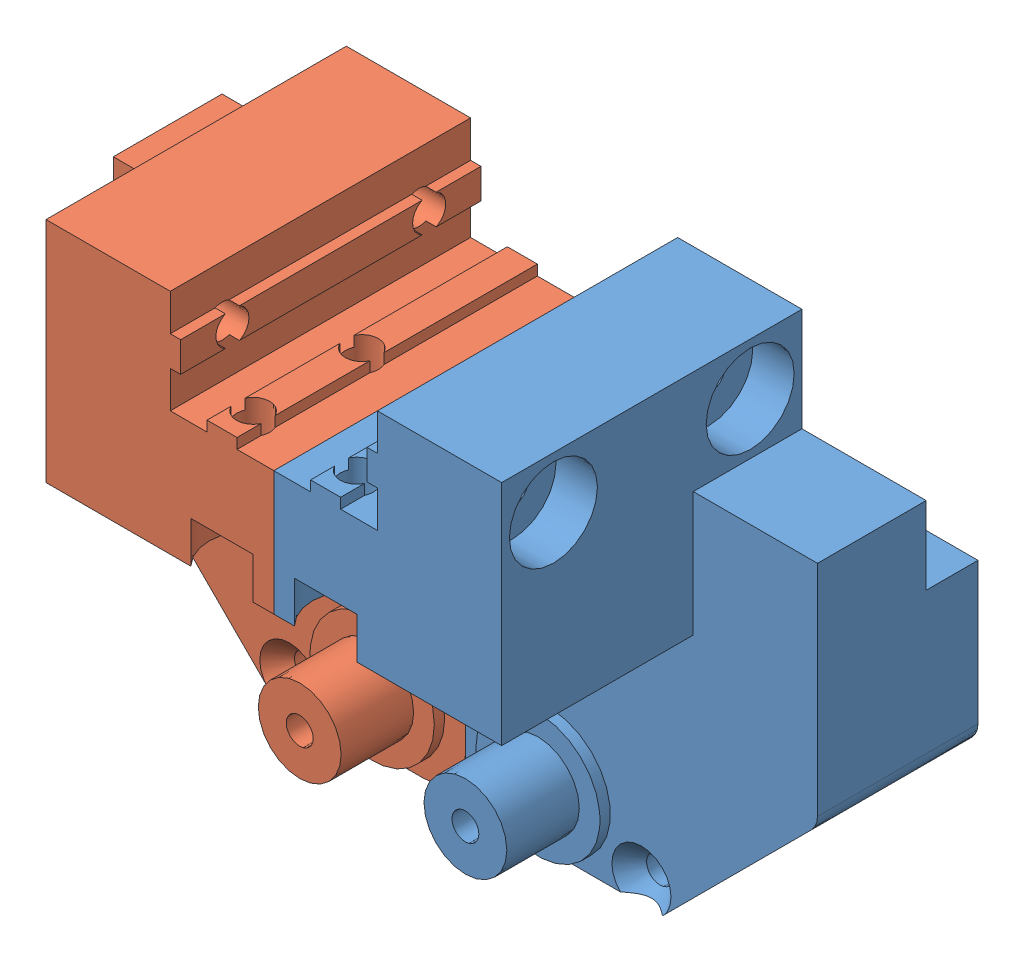
SolidWorks assembly CareerBall24mmBlockPieceAssembly, configuration Défaut. Lengths in mm.
Overall size (68 47 34).
2 component instances, 2 part files, 0 mates.
Components (placement in the parent):
- CareerBall24mmBlockPiece-1: CareerBall24mmBlockPiece [Défaut] at (-39.9962 -17.5022 22.7) size (34 47 34)
- SymétrieCareerBall24mmBlockPiece-8: SymétrieCareerBall24mmBlockPiece [Défaut] at (-73.9962 -17.5022 22.7) x (-1 0 0) z (0 0 -1) size (34 47 34)
